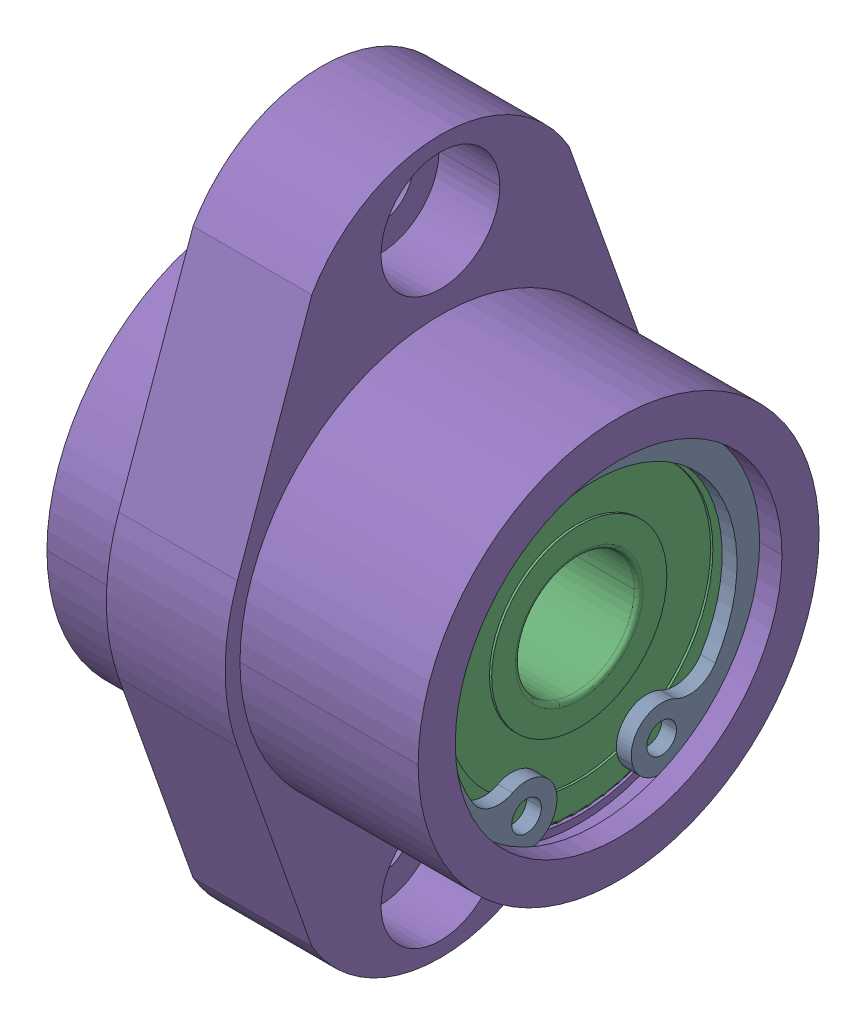
SolidWorks assembly C_BGCZB608ZZ, configuration Default. Lengths in mm.
Overall size (25 48 29).
5 component instances, 3 part files, 0 mates.
Components (placement in the parent):
- C_BGCZB608ZZ_3-1: C_BGCZB608ZZ_3 [Default] at (22.85 0 0) size (1 21.86 23)
- C_BGCZB608ZZ_3-2: C_BGCZB608ZZ_3 [Default] at (2.15 0 0) x (-1 0 0) z (0 0 -1) size (1 21.86 23)
- C_BGCZB608ZZ_6-1: C_BGCZB608ZZ_6 [Default] at (18.85 0 0) x (-1 0 0) z (0 0 1) size (7 22 22)
- C_BGCZB608ZZ_6-2: C_BGCZB608ZZ_6 [Default] at (6.15 0 0) size (7 22 22)
- C_BGCZB608ZZ_9-1: C_BGCZB608ZZ_9 [Default] at origin size (25 48 29)
